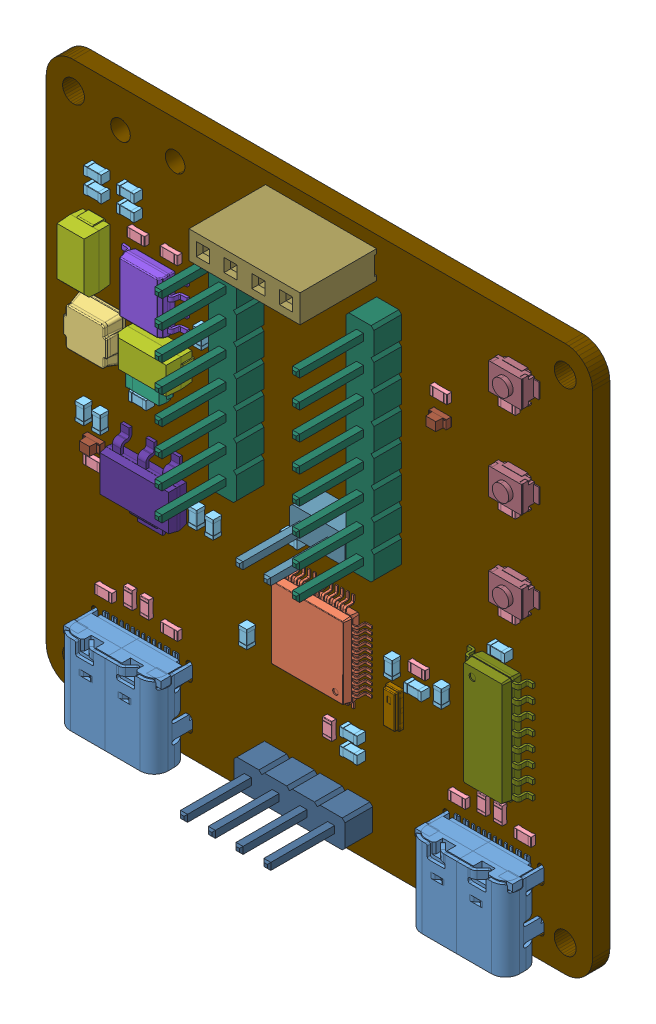
SolidWorks assembly TMC2209_TestBoard, configuration 默认. Lengths in mm.
Overall size (50 50 11.64).
114 component instances, 18 part files, 0 mates.
Components (placement in the parent):
- TMC2209_TestBoard.step-1: TMC2209_TestBoard.step [默认] at origin size (50 50 11.64)
  - USB_C_Receptacle_GCT_USB4105-xx-A_16P_TopMnt_Horizontal.step-1: USB_C_Receptacle_GCT_USB4105-xx-A_16P_TopMnt_Horizontal.step [默认] at (84.5999 -85.7499 1.63) size (8.94 7.78 4.26)
    - COMPOUND.step-1: COMPOUND.step [默认] at origin size (8.94 7.78 4.26)
  - LQFP-48_7x7mm_P0.5mm.step-1: LQFP-48_7x7mm_P0.5mm.step [默认] at (101.2699 -73.4399 1.63) x (-1 0 0) z (0 0 1) size (9 9 1.5)
    - SOLID.step-1: SOLID.step [默认] at origin size (9 9 1.5)
  - L_Bourns-SRN4018.step-1: L_Bourns-SRN4018.step [默认] at (81.2119 -59.0749 1.63) x (0 -1 0) z (0 0 1) size (4 4.09 1.8)
    - COMPOUND-0.step-1: COMPOUND-0.step [默认] at origin size (4 4.09 1.8)
  - R_0603_1608Metric.step-1: R_0603_1608Metric.step [默认] at (118.4749 -54.7599 1.63) x (-1 0 0) z (0 0 1) size (1.6 0.8 0.45)
    - SOLID-1.step-1: SOLID-1.step [默认] at origin size (1.6 0.8 0.45)
  - C_0603_1608Metric.step-1: C_0603_1608Metric.step [默认] at (80.9149 -46.8999 1.63) x (-1 0 0) z (0 0 1) size (1.6 0.8 0.8)
    - SOLID-2.step-1: SOLID-2.step [默认] at origin size (1.6 0.8 0.8)
  - CP_EIA-3216-10_Kemet-I.step-1: CP_EIA-3216-10_Kemet-I.step [默认] at (85.8749 -60.8899 1.63) size (3.4 1.8 1.2)
    - SOLID-3.step-1: SOLID-3.step [默认] at origin size (3.4 1.8 1.2)
  - C_0603_1608Metric.step-2: C_0603_1608Metric.step [默认] at (90.4899 -55.0149 1.63) x (0 1 0) z (0 0 1) size (1.6 0.8 0.8)
    - SOLID-2.step-1: SOLID-2.step [默认] at origin size (1.6 0.8 0.8)
  - SS54.step-1: SS54.step [默认] at (86.9299 -58.1799 1.63) size (5.1 2.6 2.45)
    - COMPOUND-4.step-1: COMPOUND-4.step [默认] at origin size (5.1 2.6 2.45)
  - TPS5450DDAR.step-1: TPS5450DDAR.step [默认] at (85.9819 -53.7349 1.63) x (-1 0 0) z (0 0 1) size (6.03 4.9 1.57)
    - COMPOUND-5.step-1: COMPOUND-5.step [默认] at origin size (6.03 4.9 1.57)
  - CSTCE8M00G55-R0.step-1: CSTCE8M00G55-R0.step [默认] at (107.9443 -75.8125 1.63) x (0 -1 0) z (-1 0 0) size (3.2 0.7 1.3)
    - COMPOUND-6.step-1: COMPOUND-6.step [默认] at origin size (3.2 0.7 1.3)
  - PinHeader_1x04_P2.54mm_Vertical.step-1: PinHeader_1x04_P2.54mm_Vertical.step [默认] at (96.8849 -85.9399 1.63) x (0 1 0) z (0 0 1) size (2.54 10.16 11.54)
    - SOLID-7.step-1: SOLID-7.step [默认] at origin size (2.54 10.16 11.54)
  - LED_0603_1608Metric.step-1: LED_0603_1608Metric.step [默认] at (80.4824 -68.6399 1.63) size (1.6 0.8 1.1)
    - SOLID-8.step-1: SOLID-8.step [默认] at origin size (1.6 0.8 1.1)
  - R_0603_1608Metric.step-2: R_0603_1608Metric.step [默认] at (119.9149 -80.0649 1.63) x (-1 0 0) z (0 0 1) size (1.6 0.8 0.45)
    - SOLID-1.step-1: SOLID-1.step [默认] at origin size (1.6 0.8 0.45)
  - C_0603_1608Metric.step-3: C_0603_1608Metric.step [默认] at (83.9049 -46.8999 1.63) size (1.6 0.8 0.8)
    - SOLID-2.step-1: SOLID-2.step [默认] at origin size (1.6 0.8 0.8)
  - R_0603_1608Metric.step-3: R_0603_1608Metric.step [默认] at (84.5299 -50.1499 1.63) size (1.6 0.8 0.45)
    - SOLID-1.step-1: SOLID-1.step [默认] at origin size (1.6 0.8 0.45)
  - R_0603_1608Metric.step-4: R_0603_1608Metric.step [默认] at (116.1499 -79.3149 1.63) x (0 -1 0) z (0 0 1) size (1.6 0.8 0.45)
    - SOLID-1.step-1: SOLID-1.step [默认] at origin size (1.6 0.8 0.45)
  - PinSocket_1x04_P2.54mm_Vertical.step-1: PinSocket_1x04_P2.54mm_Vertical.step [默认] at (104.8499 -41.7899 1.63) x (0 -1 0) z (0 0 1) size (2.54 10.16 10.1)
    - SOLID-9.step-1: SOLID-9.step [默认] at origin size (2.54 10.16 10.1)
  - C_0603_1608Metric.step-4: C_0603_1608Metric.step [默认] at (79.7199 -66.3699 1.63) x (0 -1 0) z (0 0 1) size (1.6 0.8 0.8)
    - SOLID-2.step-1: SOLID-2.step [默认] at origin size (1.6 0.8 0.8)
  - B3U-1000P.step-1: B3U-1000P.step [默认] at (119.0699 -60.9299 1.63) x (1 0 0) z (0 -1 0) size (4 1.6 2.5)
    - SOLID-10.step-1: SOLID-10.step [默认] at origin size (4 1.6 2.5)
  - R_0603_1608Metric.step-5: R_0603_1608Metric.step [默认] at (102.0399 -80.4249 1.63) x (0 1 0) z (0 0 1) size (1.6 0.8 0.45)
    - SOLID-1.step-1: SOLID-1.step [默认] at origin size (1.6 0.8 0.45)
  - C_0603_1608Metric.step-5: C_0603_1608Metric.step [默认] at (81.2299 -66.3699 1.63) x (0 -1 0) z (0 0 1) size (1.6 0.8 0.8)
    - SOLID-2.step-1: SOLID-2.step [默认] at origin size (1.6 0.8 0.8)
  - SS54.step-2: SS54.step [默认] at (80.5699 -53.0799 1.63) x (0 1 0) z (0 0 1) size (5.1 2.6 2.45)
    - COMPOUND-4.step-1: COMPOUND-4.step [默认] at origin size (5.1 2.6 2.45)
  - B3U-1000P.step-2: B3U-1000P.step [默认] at (119.0699 -52.6099 1.63) x (1 0 0) z (0 -1 0) size (4 1.6 2.5)
    - SOLID-10.step-1: SOLID-10.step [默认] at origin size (4 1.6 2.5)
  - R_0603_1608Metric.step-6: R_0603_1608Metric.step [默认] at (110.2049 -71.7199 1.63) x (-1 0 0) z (0 0 1) size (1.6 0.8 0.45)
    - SOLID-1.step-1: SOLID-1.step [默认] at origin size (1.6 0.8 0.45)
  - R_0603_1608Metric.step-7: R_0603_1608Metric.step [默认] at (81.5499 -79.9199 1.63) size (1.6 0.8 0.45)
    - SOLID-1.step-1: SOLID-1.step [默认] at origin size (1.6 0.8 0.45)
  - LED_0603_1608Metric.step-2: LED_0603_1608Metric.step [默认] at (112.1799 -50.8199 1.63) x (-1 0 0) z (0 0 1) size (1.6 0.8 1.1)
    - SOLID-8.step-1: SOLID-8.step [默认] at origin size (1.6 0.8 1.1)
  - R_0603_1608Metric.step-8: R_0603_1608Metric.step [默认] at (80.4699 -70.1499 1.63) x (-1 0 0) z (0 0 1) size (1.6 0.8 0.45)
    - SOLID-1.step-1: SOLID-1.step [默认] at origin size (1.6 0.8 0.45)
  - C_0603_1608Metric.step-6: C_0603_1608Metric.step [默认] at (110.2049 -73.2199 1.63) size (1.6 0.8 0.8)
    - SOLID-2.step-1: SOLID-2.step [默认] at origin size (1.6 0.8 0.8)
  - PinHeader_1x02_P2.54mm_Vertical.step-1: PinHeader_1x02_P2.54mm_Vertical.step [默认] at (101.9599 -63.3799 1.63) x (0 1 0) z (0 0 1) size (2.54 5.08 11.54)
    - SOLID-11.step-1: SOLID-11.step [默认] at origin size (2.54 5.08 11.54)
  - USB_C_Receptacle_GCT_USB4105-xx-A_16P_TopMnt_Horizontal.step-2: USB_C_Receptacle_GCT_USB4105-xx-A_16P_TopMnt_Horizontal.step [默认] at (116.7699 -85.7499 1.63) size (8.94 7.78 4.26)
    - COMPOUND.step-1: COMPOUND.step [默认] at origin size (8.94 7.78 4.26)
  - C_0603_1608Metric.step-7: C_0603_1608Metric.step [默认] at (107.9499 -72.4699 1.63) x (0 -1 0) z (0 0 1) size (1.6 0.8 0.8)
    - SOLID-2.step-1: SOLID-2.step [默认] at origin size (1.6 0.8 0.8)
  - C_0603_1608Metric.step-8: C_0603_1608Metric.step [默认] at (91.5699 -69.5099 1.63) x (0 1 0) z (0 0 1) size (1.6 0.8 0.8)
    - SOLID-2.step-1: SOLID-2.step [默认] at origin size (1.6 0.8 0.8)
  - PinHeader_1x08_P2.54mm_Vertical.step-1: PinHeader_1x08_P2.54mm_Vertical.step [默认] at (94.5549 -63.3799 1.63) x (-1 0 0) z (0 0 1) size (2.54 20.32 11.54)
    - SOLID-12.step-1: SOLID-12.step [默认] at origin size (2.54 20.32 11.54)
  - C_0603_1608Metric.step-9: C_0603_1608Metric.step [默认] at (117.8149 -66.3699 1.63) x (-1 0 0) z (0 0 1) size (1.6 0.8 0.8)
    - SOLID-2.step-1: SOLID-2.step [默认] at origin size (1.6 0.8 0.8)
  - PinHeader_1x08_P2.54mm_Vertical.step-2: PinHeader_1x08_P2.54mm_Vertical.step [默认] at (107.1449 -45.5999 1.63) size (2.54 20.32 11.54)
    - SOLID-12.step-1: SOLID-12.step [默认] at origin size (2.54 20.32 11.54)
  - R_0603_1608Metric.step-9: R_0603_1608Metric.step [默认] at (118.4749 -46.5499 1.63) x (-1 0 0) z (0 0 1) size (1.6 0.8 0.45)
    - SOLID-1.step-1: SOLID-1.step [默认] at origin size (1.6 0.8 0.45)
  - C_0603_1608Metric.step-10: C_0603_1608Metric.step [默认] at (94.6599 -76.6499 1.63) x (0 1 0) z (0 0 1) size (1.6 0.8 0.8)
    - SOLID-2.step-1: SOLID-2.step [默认] at origin size (1.6 0.8 0.8)
  - R_0603_1608Metric.step-10: R_0603_1608Metric.step [默认] at (87.5549 -79.9199 1.63) x (-1 0 0) z (0 0 1) size (1.6 0.8 0.45)
    - SOLID-1.step-1: SOLID-1.step [默认] at origin size (1.6 0.8 0.45)
  - R_0603_1608Metric.step-11: R_0603_1608Metric.step [默认] at (83.7999 -79.1699 1.63) x (0 -1 0) z (0 0 1) size (1.6 0.8 0.45)
    - SOLID-1.step-1: SOLID-1.step [默认] at origin size (1.6 0.8 0.45)
  - R_0603_1608Metric.step-12: R_0603_1608Metric.step [默认] at (112.2199 -48.8299 1.63) x (-1 0 0) z (0 0 1) size (1.6 0.8 0.45)
    - SOLID-1.step-1: SOLID-1.step [默认] at origin size (1.6 0.8 0.45)
  - C_0603_1608Metric.step-11: C_0603_1608Metric.step [默认] at (112.4599 -72.4699 1.63) x (0 1 0) z (0 0 1) size (1.6 0.8 0.8)
    - SOLID-2.step-1: SOLID-2.step [默认] at origin size (1.6 0.8 0.8)
  - C_0603_1608Metric.step-12: C_0603_1608Metric.step [默认] at (104.3299 -81.1899 1.63) x (-1 0 0) z (0 0 1) size (1.6 0.8 0.8)
    - SOLID-2.step-1: SOLID-2.step [默认] at origin size (1.6 0.8 0.8)
  - SOIC-16_3.9x9.9mm_P1.27mm.step-1: SOIC-16_3.9x9.9mm_P1.27mm.step [默认] at (117.6099 -72.3099 1.63) size (6 9.9 1.75)
    - SOLID-13.step-1: SOLID-13.step [默认] at origin size (6 9.9 1.75)
  - C_0603_1608Metric.step-13: C_0603_1608Metric.step [默认] at (104.3299 -79.6599 1.63) x (-1 0 0) z (0 0 1) size (1.6 0.8 0.8)
    - SOLID-2.step-1: SOLID-2.step [默认] at origin size (1.6 0.8 0.8)
  - C_0603_1608Metric.step-14: C_0603_1608Metric.step [默认] at (80.9149 -48.3974 1.63) x (-1 0 0) z (0 0 1) size (1.6 0.8 0.8)
    - SOLID-2.step-1: SOLID-2.step [默认] at origin size (1.6 0.8 0.8)
  - R_0603_1608Metric.step-13: R_0603_1608Metric.step [默认] at (85.3099 -79.1699 1.63) x (0 -1 0) z (0 0 1) size (1.6 0.8 0.45)
    - SOLID-1.step-1: SOLID-1.step [默认] at origin size (1.6 0.8 0.45)
  - R_0603_1608Metric.step-14: R_0603_1608Metric.step [默认] at (118.4749 -63.1699 1.63) x (-1 0 0) z (0 0 1) size (1.6 0.8 0.45)
    - SOLID-1.step-1: SOLID-1.step [默认] at origin size (1.6 0.8 0.45)
  - C_0603_1608Metric.step-15: C_0603_1608Metric.step [默认] at (85.0099 -62.7399 1.63) size (1.6 0.8 0.8)
    - SOLID-2.step-1: SOLID-2.step [默认] at origin size (1.6 0.8 0.8)
  - SOT-223.step-1: SOT-223.step [默认] at (85.6599 -69.2899 1.63) x (0 -1 0) z (0 0 1) size (7 6.5 1.7)
    - SOLID-14.step-1: SOLID-14.step [默认] at origin size (7 6.5 1.7)
  - C_0603_1608Metric.step-16: C_0603_1608Metric.step [默认] at (98.8599 -66.8599 1.63) size (1.6 0.8 0.8)
    - SOLID-2.step-1: SOLID-2.step [默认] at origin size (1.6 0.8 0.8)
  - C_0603_1608Metric.step-17: C_0603_1608Metric.step [默认] at (83.9049 -48.3974 1.63) size (1.6 0.8 0.8)
    - SOLID-2.step-1: SOLID-2.step [默认] at origin size (1.6 0.8 0.8)
  - C_0603_1608Metric.step-18: C_0603_1608Metric.step [默认] at (90.0499 -69.5099 1.63) x (0 1 0) z (0 0 1) size (1.6 0.8 0.8)
    - SOLID-2.step-1: SOLID-2.step [默认] at origin size (1.6 0.8 0.8)
  - R_0603_1608Metric.step-15: R_0603_1608Metric.step [默认] at (87.5449 -50.1499 1.63) size (1.6 0.8 0.45)
    - SOLID-1.step-1: SOLID-1.step [默认] at origin size (1.6 0.8 0.45)
  - B3U-1000P.step-3: B3U-1000P.step [默认] at (119.0699 -44.2699 1.63) x (1 0 0) z (0 -1 0) size (4 1.6 2.5)
    - SOLID-10.step-1: SOLID-10.step [默认] at origin size (4 1.6 2.5)
  - R_0603_1608Metric.step-16: R_0603_1608Metric.step [默认] at (117.6599 -79.3149 1.63) x (0 -1 0) z (0 0 1) size (1.6 0.8 0.45)
    - SOLID-1.step-1: SOLID-1.step [默认] at origin size (1.6 0.8 0.45)
  - R_0603_1608Metric.step-17: R_0603_1608Metric.step [默认] at (113.8899 -80.0649 1.63) size (1.6 0.8 0.45)
    - SOLID-1.step-1: SOLID-1.step [默认] at origin size (1.6 0.8 0.45)
  - TMC2209_TestBoard PCB.step-1: TMC2209_TestBoard PCB.step [默认] at origin size (50 50 1.58)
